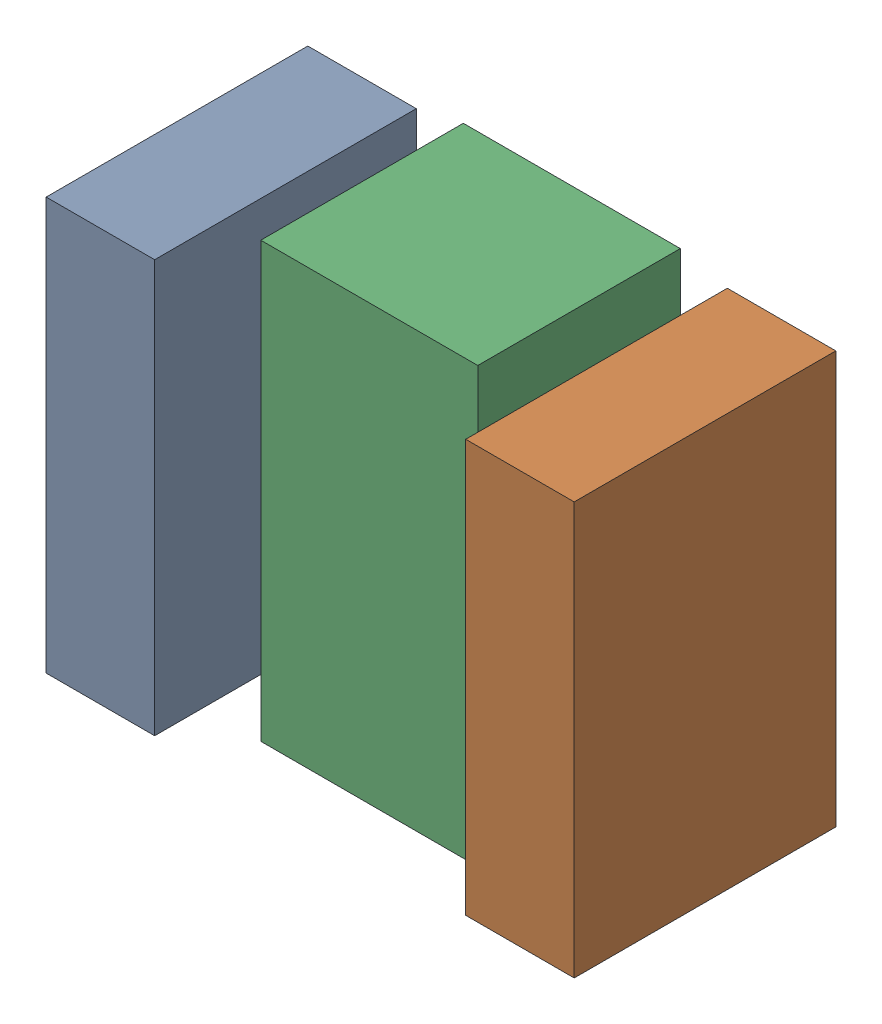
SolidWorks assembly C7_Motor_2Kanaloa_v2.0.0_Motor, configuration Default. Lengths in mm.
Overall size (3.65 3 1.81).
6 component instances, 2 part files, 0 mates.
Components (placement in the parent):
- 334788400-1: 334788400 [Default] at (144.806 56.642 0) size (0.75 2.85 1.81)
  - Extruded_5-1: Extruded_5 [Default] at origin size (0.75 2.85 1.81)
- 334788400-2: 334788400 [Default] at (147.706 56.642 0) size (0.75 2.85 1.81)
  - Extruded_5-1: Extruded_5 [Default] at origin size (0.75 2.85 1.81)
- 334788656-1: 334788656 [Default] at (146.256 56.642 0) size (1.5 3 1.4)
  - Extruded_1-1: Extruded_1 [Default] at origin size (1.5 3 1.4)
